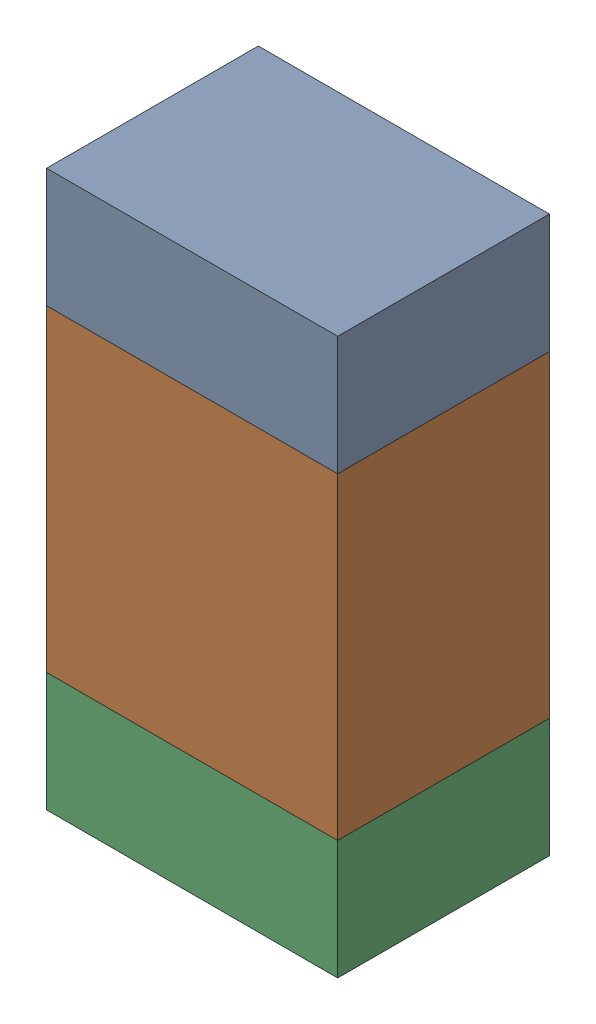
SolidWorks assembly R601_2PCB, configuration Default. Lengths in mm.
Overall size (0.55 1.05 0.4).
6 component instances, 2 part files, 0 mates.
Components (placement in the parent):
- 846483288-1: 846483288 [Default] at (103.9999 104.9624 -2.0638) size (0.55 0.22 0.4)
  - Extruded_12-1: Extruded_12 [Default] at origin size (0.55 0.22 0.4)
- 846483424-1: 846483424 [Default] at (103.9999 104.5499 -2.0638) size (0.55 0.6 0.4)
  - Extruded_13-1: Extruded_13 [Default] at origin size (0.55 0.6 0.4)
- 846483288-2: 846483288 [Default] at (103.9999 104.1374 -2.0638) size (0.55 0.22 0.4)
  - Extruded_12-1: Extruded_12 [Default] at origin size (0.55 0.22 0.4)
